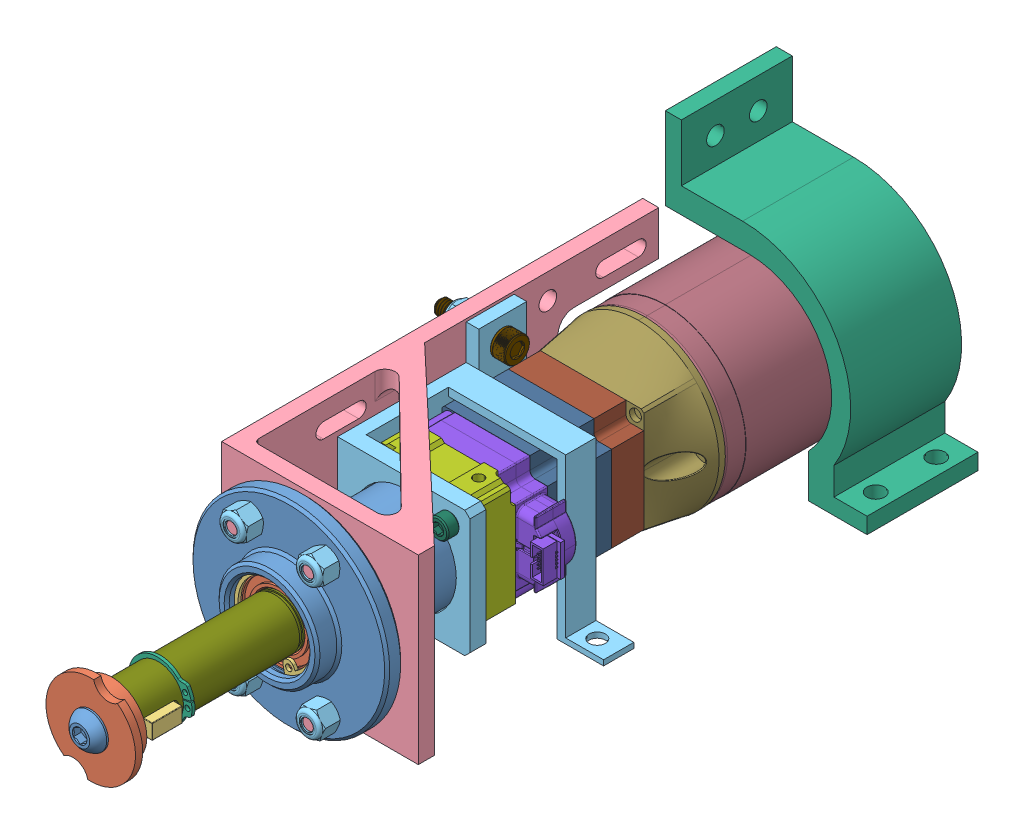
SolidWorks assembly PB2023-M054 DRIVETRAIN ASSEMBLY-v1, configuration Default. Lengths in mm.
Overall size (93.83 163.91 344.65).
42 component instances, 24 part files, 23 mates.
Components (placement in the parent):
- A12220103_FRONT_BRACKET_ASSEMBLY-1: A12220103_FRONT_BRACKET_ASSEMBLY [Default] at origin size (78 78 534.65)
  - A12220101_FRONT_CASE_ASSEMBLY-1: A12220101_FRONT_CASE_ASSEMBLY [Default] at origin size (78 78 141.2)
    - 12220103_FRONT_HOUSING-1: 12220103_FRONT_HOUSING [Default] at (-52 141.0744 -192.9876) x (0 0 -1) z (1 0 0) size (60 78 78)
    - BALL BEARING-1: BALL BEARING [6656K203] at origin size (32 32 10)
    - BALL BEARING-2: BALL BEARING [6656K203] at (0 0 41) size (32 32 10)
    - Internal Retaining Ring (98455A129)-1: Internal Retaining Ring (98455A129) [98455A129] at (0.0361 0.7992 46) x (0.998982 -0.045107 0) z (0 0 1) size (34.4 33.81 1.2)
  - M6 x 20mm Steel Hex Head Screw (91310A333)-2: M6 x 20mm Steel Hex Head Screw (91310A333) [91310A333] at (-15.125 -26.1973 37.15) x (0 0 1) z (-0.44141 0.897306 0) size (24.4 11.55 10)
  - M6 x 1mm Steel Hex LockNut (90592A016)-1: M6 x 1mm Steel Hex LockNut (90592A016) [97260A101] at (15.125 -26.1973 41.85) x (0.928554 -0.371196 0) z (-0.371196 -0.928554 0) size (10 8.38 11.55)
  - 20MM External Retaining Ring (98541A123)-4: 20MM External Retaining Ring (98541A123) [98541A123] at (0 0 92.94) x (0 0 1) z (-0.186581 0.98244 0) size (1.2 25.1 22.76)
  - A12220110_FRONT_SHAFT_ASSEMBLY-1: A12220110_FRONT_SHAFT_ASSEMBLY [Default] at (1.7896 0 -19.01) x (0 -1 0) z (0 0 1) size (64.01 67.32 307.03)
    - A12220105_MOTOR_BRACKET_ASSEMBLY-1: A12220105_MOTOR_BRACKET_ASSEMBLY [Default] at origin size (64.01 67.32 280.24) (flexible)
      - 12220106-051 MiniCIM Motor Assembly-1: 12220106-051 MiniCIM Motor Assembly [Default] at origin size (64.01 67.32 218.97)
        - Gearbox Assembly-1: Gearbox Assembly [Default] at (34.0244 -12.4567 -92.7758) x (0 0 1) z (-1 0 0) size (123.35 56.32 44.45)
          - Output Housing-2: Output Housing [Default] at (64.8023 -0.856 18.2213) x (1 0 0) z (0 -1 0) size (75.7 44.45 56.32)
            - Housing-1: Housing [Default] at (19.8785 -6.4219 -11.5232) size (18.13 44.45 42)
            - Encoder.step-1: Encoder.step [Default] at (12.6785 15.8031 -11.5232) x (0 0 1) z (-1 0 0) size (56.32 42 21.21)
            - Gearbox_output_shaft-1: Gearbox_output_shaft [Default] at origin size (63.51 17 17)
          - Ring Gears-1: Ring Gears [Default] at (71.9808 10.6671 11.7994) x (1 0 0) z (0 -1 0) size (32.2 42 42)
          - Ring Gear Stage 3-1: Ring Gear Stage 3 [Default] at (59.2808 10.6671 11.7994) x (1 0 0) z (0 -1 0) size (28.65 42 42)
        - CIM Adaptor.step-1: CIM Adaptor.step [Default] at (0 -1.7896 -68.72) x (0 -1 0) z (-1 0 0) size (64.01 21.63 64.01)
        - Mini CIM-1: Mini CIM [Default] at (0 -1.7896 -80.245) x (0 0 -1) z (1 0 0) size (101.22 64.01 64.01)
        - 8-32 X 3IN LG - Black-Oxide Alloy Steel Socket Head Screw (90044A516)-1: 8-32 X 3IN LG - Black-Oxide Alloy Steel Socket Head Screw (90044A516) [90044A516] at (17.5 15.7104 -75.245) x (-0.08536 0.99635 0) z (0 0 -1) size (6.86 6.86 81.33)
        - 8-32 X 3IN LG - Black-Oxide Alloy Steel Socket Head Screw (90044A516)-3: 8-32 X 3IN LG - Black-Oxide Alloy Steel Socket Head Screw (90044A516) [90044A516] at (-17.5 -19.2896 -75.245) x (-0.242255 0.970213 0) z (0 0 -1) size (6.86 6.86 81.33)
      - 10-32 X 0.875IN LG - Black-Oxide Alloy Steel Socket Head Screw (91251A346)-1: 10-32 X 0.875IN LG - Black-Oxide Alloy Steel Socket Head Screw (91251A346) [91251A346] at (-17.9605 16.1709 6.1805) x (0.130335 0.99147 0) z (0 0 1) size (7.94 7.94 27.67)
      - 10-32 X 0.875IN LG - Black-Oxide Alloy Steel Socket Head Screw (91251A346)-2: 10-32 X 0.875IN LG - Black-Oxide Alloy Steel Socket Head Screw (91251A346) [91251A346] at (17.9605 -19.7501 6.1805) x (0.872398 0.488796 0) z (0 0 1) size (7.94 7.94 27.67)
    - PB2023-M005 ROTARY SHAFT-1: PB2023-M005 ROTARY SHAFT [Default] at (0 -1.7896 136.57) x (0 0 -1) z (1 0 0) size (126.56 25 25)
    - 12220110_MOTOR_KEY-1: 12220110_MOTOR_KEY [Default] at (0 5.1764 16.3975) size (3.17 4.76 26.16)
  - M6 x 20mm Steel Hex Head Screw (91310A333)-7: M6 x 20mm Steel Hex Head Screw (91310A333) [91310A333] at (15.125 -26.1973 37.15) x (0 0 1) z (0.78025 0.625468 0) size (24.4 11.55 10)
  - M6 x 20mm Steel Hex Head Screw (91310A333)-9: M6 x 20mm Steel Hex Head Screw (91310A333) [91310A333] at (15.125 26.1973 37.15) x (0 0 1) z (0.877007 0.480477 0) size (24.4 11.55 10)
  - M6 x 20mm Steel Hex Head Screw (91310A333)-11: M6 x 20mm Steel Hex Head Screw (91310A333) [91310A333] at (-15.0958 26.1466 37.15) x (0 0 1) z (0.947118 0.320887 0) size (24.4 11.55 10)
  - M6 x 1mm Steel Hex LockNut (90592A016)-7: M6 x 1mm Steel Hex LockNut (90592A016) [97260A101] at (-15.125 -26.1973 41.85) x (0.975663 -0.219276 0) z (-0.219276 -0.975663 0) size (10 8.38 11.55)
  - M6 x 1mm Steel Hex LockNut (90592A016)-9: M6 x 1mm Steel Hex LockNut (90592A016) [97260A101] at (-15.125 26.1973 41.85) x (0.995642 -0.093258 0) z (-0.093258 -0.995642 0) size (10 8.38 11.55)
  - M6 x 1mm Steel Hex LockNut (90592A016)-11: M6 x 1mm Steel Hex LockNut (90592A016) [97260A101] at (15.2049 26.151 41.85) x (1 -0.000046 0) z (-0.000046 -1 0) size (10 8.38 11.55)
- M6 x 25mm Steel Socket Head Screw (91290A330)-1: M6 x 25mm Steel Socket Head Screw (91290A330) [91290A330] at (-31.155 30 -64.48) x (0 -0.901175 -0.433456) z (1 0 0) size (10 10 31.46)
- M6 x 1mm Steel Hex LockNut (90592A016)-1: M6 x 1mm Steel Hex LockNut (90592A016) [97260A101] at (-33 -30 -64.48) x (0 0.608626 0.793457) z (0 -0.793457 0.608626) size (10 8.38 11.55)
- M6 x 1mm Steel Hex LockNut (90592A016)-2: M6 x 1mm Steel Hex LockNut (90592A016) [97260A101] at (-33 30 -64.48) x (0 -0.994883 0.101031) z (0 -0.101031 -0.994883) size (10 8.38 11.55)
- M8 X 20MM - 18-8 Stainless Steel Button Head Hex Drive Screws (97763A444)-1: M8 X 20MM - 18-8 Stainless Steel Button Head Hex Drive Screws (97763A444) [97763A444] at (0 0 124.825) x (0.999813 0.019347 0) z (0 0 1) size (14 14 25.15)
- PB2023-M006 WHEEL END CAP CUSTOM WASHER-1: PB2023-M006 WHEEL END CAP CUSTOM WASHER [Default] at (0 0 117.56) x (0 0 -1) z (-0.345262 -0.938506 0) size (8.5 35.5 34.05)
- 98870A743_Machine Key-1: 98870A743_Machine Key [98870A743] at (10 0 103.06) size (6 6 12)
- braquette bleu-1: braquette bleu [Default] at (-33 40 35.5) x (0 0 -1) z (0 -1 0) size (205.75 78 138.28)
- braquette gearbox-3: braquette gearbox [Default] at (-21.66 25 -4.13) x (0 0 -1) z (-1 0 0) size (72.34 80.66 66.5)
- braquette moteur- v2-1: braquette moteur- v2 [Default] at (0 -0.0033 -184.471) x (0 1 0) z (0 0 -1) size (123.62 80 44)
Mates (geometry in assembly coordinates):
- Coincident4: coordinate: point of A12220103_FRONT_BRACKET_ASSEMBLY-1
- Concentric5: concentric aligned: cylinder of A12220103_FRONT_BRACKET_ASSEMBLY-1/12220105_SUPPORT_BRACKET-1 through (-16.8 -30 -64.48) axis (-1 0 0) radius 3.5; cylinder of M6 x 1mm Steel Hex LockNut (90592A016)-1 through (-39.85 -30 -64.48) axis (-1 0 0) radius 2.375
- Coincident7: coincident anti-aligned: plane of A12220103_FRONT_BRACKET_ASSEMBLY-1/12220105_SUPPORT_BRACKET-1 through (-33 0 35.5) normal (-1 0 0); plane of M6 x 1mm Steel Hex LockNut (90592A016)-1 through (-33 -26.1716 -73.7181) normal (1 0 0)
- Concentric6: concentric aligned: cylinder of A12220103_FRONT_BRACKET_ASSEMBLY-1/12220105_SUPPORT_BRACKET-1 through (-16.8 30 -64.48) axis (-1 0 0) radius 3.5; cylinder of M6 x 1mm Steel Hex LockNut (90592A016)-2 through (-39.85 30 -64.48) axis (-1 0 0) radius 2.375
- Coincident8: coincident anti-aligned: plane of A12220103_FRONT_BRACKET_ASSEMBLY-1/12220105_SUPPORT_BRACKET-1 through (-33 0 35.5) normal (-1 0 0); plane of M6 x 1mm Steel Hex LockNut (90592A016)-2 through (-33 35.8494 -56.3692) normal (1 0 0)
- Concentric15: concentric aligned: cylinder of A12220103_FRONT_BRACKET_ASSEMBLY-1/A12220110_FRONT_SHAFT_ASSEMBLY-1/A12220105_MOTOR_BRACKET_ASSEMBLY-1/12220106_MOTOR_BRACKET-1 through (-21.655 30 -64.48) axis (-1 0 0) radius 3.5; cylinder of M6 x 25mm Steel Socket Head Screw (91290A330)-1 through (-46.655 30 -64.48) axis (-1 0 0) radius 5
- Coincident21: coincident anti-aligned: plane of A12220103_FRONT_BRACKET_ASSEMBLY-1/A12220110_FRONT_SHAFT_ASSEMBLY-1/A12220105_MOTOR_BRACKET_ASSEMBLY-1/12220106_MOTOR_BRACKET-1 through (-21.655 0 -10.48) normal (1 0 0); plane of M6 x 25mm Steel Socket Head Screw (91290A330)-1 through (-21.655 34.2355 -62.4428) normal (-1 0 0)
- Concentric17: concentric aligned: cylinder of M8 X 20MM - 18-8 Stainless Steel Button Head Hex Drive Screws (97763A444)-1 through (0 0 124.825) axis (0 0 1) radius 7; cylinder of 12220117_CUSTOM_WASHER-1 through (0 0 120.425) axis (0 0 1) radius 5
- Coincident22: coincident anti-aligned: plane of M8 X 20MM - 18-8 Stainless Steel Button Head Hex Drive Screws (97763A444)-1 through (0.1354 -6.9987 120.425) normal (0 0 -1); plane of 12220117_CUSTOM_WASHER-1 through (3.9887 -1.4674 120.425) normal (0 0 1)
- Concentric18: concentric aligned: circle of A12220103_FRONT_BRACKET_ASSEMBLY-1/A12220110_FRONT_SHAFT_ASSEMBLY-1/12220102_FRONT_SHAFT-1; circle of 12220117_CUSTOM_WASHER-1
- Coincident23: coincident anti-aligned: plane of A12220103_FRONT_BRACKET_ASSEMBLY-1/A12220110_FRONT_SHAFT_ASSEMBLY-1/12220102_SHAFT-1 through (0 0 117.56) normal (0 0 1); plane of 12220117_CUSTOM_WASHER-1 through (3.9887 -1.4674 117.56) normal (0 0 -1)
- Coincident24: coincident anti-aligned: plane of A12220103_FRONT_BRACKET_ASSEMBLY-1/A12220110_FRONT_SHAFT_ASSEMBLY-1/12220102_SHAFT-1 through (0 -3 95.56) normal (0 1 0); plane of 98870A743_Machine Key-1 through (13 -3 109.06) normal (0 -1 0)
- Coincident25: coincident anti-aligned: plane of A12220103_FRONT_BRACKET_ASSEMBLY-1/A12220110_FRONT_SHAFT_ASSEMBLY-1/12220102_SHAFT-1 through (7 0 95.56) normal (1 0 0); plane of 98870A743_Machine Key-1 through (7 -3 109.06) normal (-1 0 0)
- Distance1: distance = 1.5 mm anti-aligned: plane of 98870A743_Machine Key-1 through (10 0 97.06) normal (0 0 -1); plane of A12220103_FRONT_BRACKET_ASSEMBLY-1/A12220110_FRONT_SHAFT_ASSEMBLY-1/12220102_SHAFT-1 through (0 0 95.56) normal (0 0 1)
- Concentric19: concentric aligned: circle of A12220103_FRONT_BRACKET_ASSEMBLY-1/A12220101_FRONT_CASE_ASSEMBLY-1/12220103_FRONT_HOUSING-1; circle of braquette bleu-1
- Parallel1: parallel aligned: line of A12220103_FRONT_BRACKET_ASSEMBLY-1/A12220110_FRONT_SHAFT_ASSEMBLY-1/A12220105_MOTOR_BRACKET_ASSEMBLY-1/12220106_MOTOR_BRACKET-1 through (25.825 -23 -4.13) axis (0 1 0); line of braquette bleu-1 through (45 -32 29.15) axis (0 1 0)
- Coincident27: coincident anti-aligned: plane of A12220103_FRONT_BRACKET_ASSEMBLY-1/A12220101_FRONT_CASE_ASSEMBLY-1/12220103_FRONT_HOUSING-1 through (0 0 35.5) normal (0 0 -1); plane of braquette bleu-1 through (-33 -40 35.5) normal (0 0 1)
- Concentric20: concentric anti-aligned: circle of A12220103_FRONT_BRACKET_ASSEMBLY-1/A12220101_FRONT_CASE_ASSEMBLY-1/12220103_FRONT_HOUSING-1; circle of braquette gearbox-3
- Coincident28: coincident anti-aligned: plane of A12220103_FRONT_BRACKET_ASSEMBLY-1/A12220110_FRONT_SHAFT_ASSEMBLY-1/A12220105_MOTOR_BRACKET_ASSEMBLY-1/10-32 X 0.875IN LG - Black-Oxide Alloy Steel Socket Head Screw (91251A346)-1 through (18.4149 21.4169 -4.13) normal (0 0 -1); circle of braquette gearbox-3
- Concentric22: concentric aligned: circle of A12220103_FRONT_BRACKET_ASSEMBLY-1/A12220110_FRONT_SHAFT_ASSEMBLY-1/A12220105_MOTOR_BRACKET_ASSEMBLY-1/12220106-051 MiniCIM Motor Assembly-1/Mini CIM-1; circle of braquette moteur- v2-1
- Parallel3: parallel aligned: plane of A12220103_FRONT_BRACKET_ASSEMBLY-1/A12220110_FRONT_SHAFT_ASSEMBLY-1/A12220105_MOTOR_BRACKET_ASSEMBLY-1/12220106-051 MiniCIM Motor Assembly-1/Gearbox Assembly-1/Ring Gears-1 through (-21 -21 -39.805) normal (0 -1 0); plane of braquette gearbox-3 through (-26.66 -25 -4.13) normal (0 -1 0)
- Parallel5: parallel aligned: plane of braquette bleu-1 through (-33 -40 35.5) normal (-1 0 0); plane of braquette moteur- v2-1 through (-33 33 -140.471) normal (-1 0 0)
- Coincident33: coincident aligned: plane of A12220103_FRONT_BRACKET_ASSEMBLY-1/A12220110_FRONT_SHAFT_ASSEMBLY-1/A12220105_MOTOR_BRACKET_ASSEMBLY-1/12220106-051 MiniCIM Motor Assembly-1/Mini CIM-1 through (31.877 0 -184.471) normal (0 0 -1); plane of braquette moteur- v2-1 through (-2.3696 0.1271 -184.471) normal (0 0 -1)
